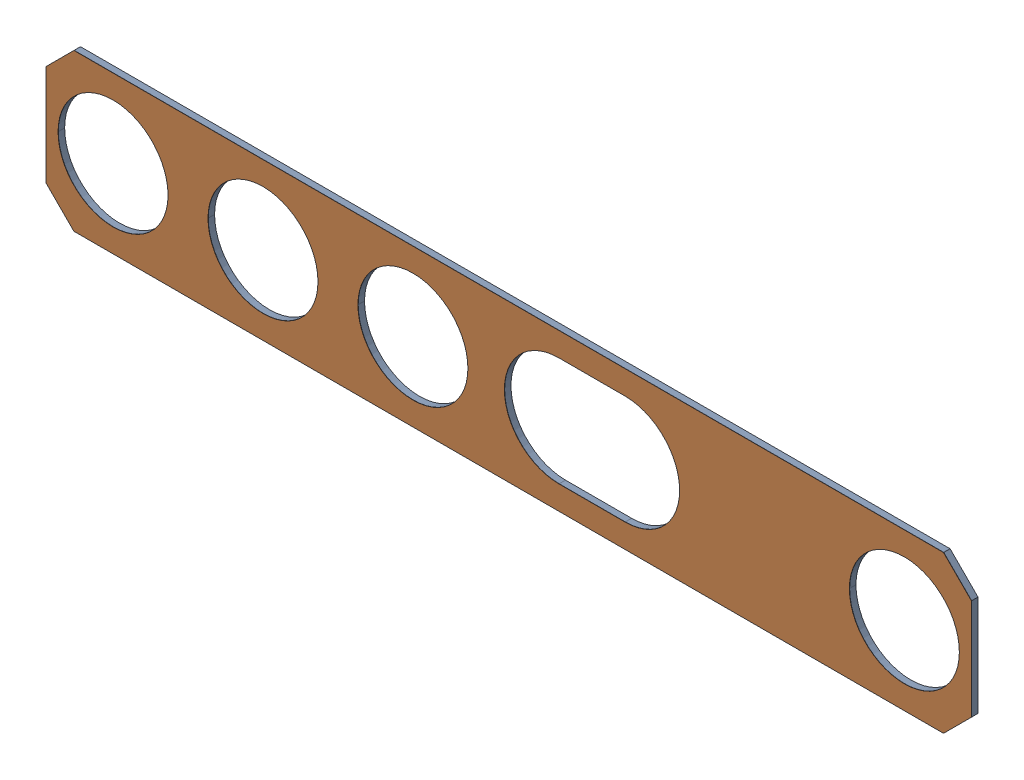
SolidWorks assembly MEC060312_ASM_4_ASM, configuration MEC060312_ASM_4_ASM. Lengths in mm.
Overall size (111.1 18.8 0.79).
2 component instances, 2 part files, 0 mates.
Components (placement in the parent):
- DS5_0390_FOAM_FRONT_D455_3-1: DS5_0390_FOAM_FRONT_D455_3 [DS5_0390_FOAM_FRONT_D455_3] at origin size (111.1 18.8 0.76)
- DS5_0390_ADHESIVE_D455_2-1: DS5_0390_ADHESIVE_D455_2 [DS5_0390_ADHESIVE_D455_2] at (0 0 -1.32) size (111.1 18.8 0.03)
